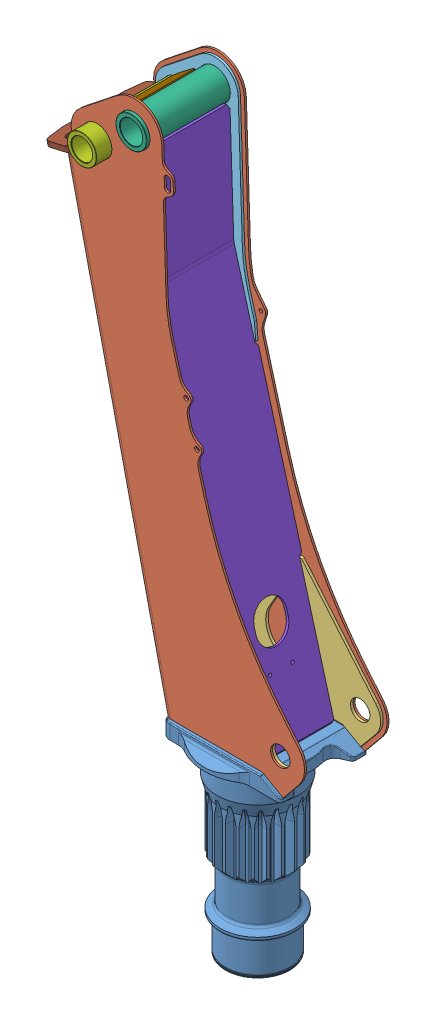
SolidWorks assembly 6344051, configuration Default. Lengths in mm.
Overall size (806.83 2259.1 354).
15 component instances, 12 part files, 31 mates.
Components (placement in the parent):
- 6344052-1: 6344052 [Default] at origin size (370 610 330)
- 6344053-1: 6344053 [Default] at (-268.9944 20.2009 -130.1889) x (0.974956 0.222399 0) z (0 0 1) size (566.48 1735.19 260.58)
  - 6344054-1: 6344054 [Default] at origin size (438.19 1703.77 260.58)
  - 6344055-2: 6344055 [6344055] at (480 -4.567 246.3777) x (0.974956 -0.222399 0) z (0 0 1) size (406.29 417 8)
  - 6344055-1: 6344055 [6344056] at (480 -4.567 6) x (0.974956 -0.222399 0) z (0 0 1) size (406.29 417 8)
  - 6344057-1: 6344057 [Default med affasning + nedslibning af spids] at (122.8111 3 130.1889) x (0 -1 0) z (1 0 0) size (320 185 10)
  - 6344058-1: 6344058 [Default] at (362.8595 1505.2986 6) x (0.974956 -0.222399 0) z (0 0 1) size (310 700 7)
  - 6344058-2: 6344058 [Default] at (362.8595 1505.2986 247.3777) x (0.974956 -0.222399 0) z (0 0 1) size (310 700 7)
- 6344059-1: 6344059 [boret] at (-250 1568.5 0) x (0 0 1) z (0.5 -0.866025 0) size (280 95 95)
- 6344061-1: 6344061 [boret] at (-365 1483.5 0) x (0 0 1) z (0.5 -0.866025 0) size (354 90 90)
- 6344062-1: 6344062 [Default] at (121.7385 48.8771 0) x (0 0 1) z (-0.964109 -0.265508 0) size (248 1528.91 93.1)
- 6344063-1: 6344063 [Default] at (-371.2649 1535.397 0) x (0 0 -1) z (0.608359 -0.793662 0) size (231 90 8)
- 6344065-1: 6344065 [Default] at (-401.9244 1447.417 0) x (0 0 -1) z (0.974956 0.222399 0) size (231 125 8)
- 6344066-1: 6344066 [Default] at (-469.5822 1424.7701 0) x (0 0 1) z (-0.222399 0.974956 0) size (318 109.52 26)
- 6344064-1: 6344064 [Default] at (125.6828 157.1547 138.1889) x (-0.906308 0.422618 0) z (0 0 -1) size (50.57 60 8)
Mates (geometry in assembly coordinates):
- Distance3: distance = 250 mm: line of 6344053-1/6344054-1 through (-250 1568.5 -124.1889) axis (0 0 -1); plane of assembly through (0 0 0) normal (1 0 0)
- Concentric1: concentric anti-aligned: cylinder of 6344053-1/6344054-1 through (-250 1568.5 124.1889) axis (0 0 1) radius 48.5; cylinder of 6344059-1 through (-250 1568.5 -140) axis (0 0 -1) radius 47.5
- Coincident5: coincident aligned: plane of 6344059-1 through (-250 1568.5 0) normal (0 0 1); plane of assembly through (0 0 0) normal (0 0 1)
- Angle1: planar angle = 2.617994 rad aligned: plane of 6344059-1 through (-250 1568.5 0) normal (-0.866025 -0.5 0); plane of assembly through (0 0 0) normal (1 0 0)
- Concentric2: concentric anti-aligned: cylinder of 6344053-1/6344054-1 through (-365 1483.5 124.1889) axis (0 0 1) radius 46; cylinder of 6344061-1 through (-365 1483.5 -177) axis (0 0 -1) radius 45
- Coincident7: coincident aligned: plane of 6344061-1 through (-365 1483.5 0) normal (0 0 1); plane of assembly through (0 0 0) normal (0 0 1)
- Angle2: planar angle = 2.617994 rad aligned: plane of 6344061-1 through (-365 1483.5 0) normal (-0.866025 -0.5 0); plane of assembly through (0 0 0) normal (1 0 0)
- Distance5: distance = 65 mm anti-aligned: plane of 6344053-1/6344054-1 through (-469.07 1449.5035 -136.8356) normal (0.974956 0.222399 0); plane of 6344065-1 through (-375.2365 1330.4224 0) normal (-0.974956 -0.222399 0)
- Coincident9: coincident: cylinder of 6344061-1 through (-365 1483.5 -177) axis (0 0 -1) radius 45; line of 6344065-1 through (-394.1248 1449.1962 -103.8944) axis (0 0 1)
- Coincident10: coincident anti-aligned: plane of 6344065-1 through (-401.9244 1447.417 0) normal (0 0 -1); plane of assembly through (0 0 0) normal (0 0 1)
- Coincident11: coincident aligned: plane of 6344066-1 through (-469.5822 1424.7701 0) normal (0 0 1); plane of assembly through (0 0 0) normal (0 0 1)
- Coincident12: coincident anti-aligned: plane of 6344053-1/6344054-1 through (-474.9198 1448.1691 -136.8356) normal (-0.974956 -0.222399 0); plane of 6344066-1 through (-472.9182 1439.3945 -114) normal (0.974956 0.222399 0)
- Distance6: distance = 6 mm aligned: plane of 6344053-1/6344054-1 through (-465.7341 1434.8791 -136.8356) normal (-0.222399 0.974956 0); plane of 6344066-1 through (-404.6713 1454.9624 156) normal (-0.222399 0.974956 0)
- Coincident14: coincident aligned: plane of 6344062-1 through (121.7385 48.8771 0) normal (0 0 1); plane of assembly through (0 0 0) normal (0 0 1)
- Coincident15: coincident: cylinder of 6344059-1 through (-250 1568.5 -140) axis (0 0 -1) radius 47.5; line of 6344062-1 through (-209.6483 1543.4403 104.3944) axis (0 0 -1)
- Parallel1: parallel aligned: plane of 6344053-1/6344054-1 through (-165.0443 1571.2441 -124.1889) normal (0.999479 0.032283 0); plane of 6344062-1 through (-150.8366 9.5465 -108.6459) normal (0.999452 0.033105 0)
- Tangent1: tangent aligned: cylinder of 6344059-1 through (-250 1568.5 -140) axis (0 0 -1) radius 47.5; plane of 6344062-1 through (-150.8366 9.5465 -108.6459) normal (0.999452 0.033105 0)
- Coincident17: coincident anti-aligned: plane of 6344053-1/6344054-1 through (-722.2141 1391.7582 130.1889) normal (0 0 1); plane of 6344064-1 through (125.6828 157.1547 130.1889) normal (0 0 -1)
- Coincident18: coincident: line of 6344053-1/6344054-1 through (200 122.5 124.1889) axis (0 0 1); plane of 6344064-1 through (125.6828 157.1547 138.1889) normal (0.422618 0.906308 0)
- Distance7: distance = 82 mm: line of 6344053-1/6344054-1 through (200 122.5 124.1889) axis (0 0 1); plane of 6344064-1 through (125.6828 157.1547 138.1889) normal (-0.906308 0.422618 0)
- Angle3: planar angle = 3.577925 rad anti-aligned: plane of 6344064-1 through (125.6828 157.1547 138.1889) normal (0.422618 0.906308 0); plane of assembly through (0 0 0) normal (0 1 0)
- Coincident19: coincident anti-aligned: plane of 6344059-1 through (-250 1568.5 0) normal (0 0 1); plane of 6344063-1 through (-371.2649 1535.397 0) normal (0 0 -1)
- Coincident21: coincident: cylinder of 6344059-1 through (-250 1568.5 -140) axis (0 0 -1) radius 47.5; line of 6344063-1 through (-294.9684 1583.8 -103.8944) axis (0 0 1)
- Tangent3: tangent aligned: cylinder of 6344059-1 through (-250 1568.5 -140) axis (0 0 -1) radius 47.5; plane of 6344063-1 through (-368.8839 1537.2221 -103.8944) normal (-0.608359 0.793662 0)
- Tangent4: tangent aligned: cylinder of 6344061-1 through (-365 1483.5 -177) axis (0 0 -1) radius 45; plane of 6344063-1 through (-368.8839 1537.2221 -103.8944) normal (-0.608359 0.793662 0)
- Distance8: distance = 95 mm: line of 6344053-1/6344055-1 through (200 122.5 -116.1889) axis (0 0 -1); plane of 6344062-1 through (120.942 51.7694 -108.6459) normal (0.964109 0.265508 0)
- Coincident22: coincident aligned: plane of 6344052-1 through (0 0 0) normal (1 0 0); plane of assembly through (0 0 0) normal (1 0 0)
- Coincident23: coincident aligned: plane of 6344052-1 through (0 0 0) normal (0 0 1); plane of assembly through (0 0 0) normal (0 0 1)
- Coincident24: coincident aligned: plane of 6344052-1 through (0 0 0) normal (0 1 0); plane of assembly through (0 0 0) normal (0 1 0)
- Distance9: distance = 2 mm anti-aligned: plane of 6344052-1 through (188.4846 45 -49.9855) normal (0 1 0); plane of 6344053-1/6344054-1 through (-150.3861 47 124.1889) normal (0 -1 0)
- Coincident26: coincident aligned: plane of 6344053-1/6344054-1 through (-268.9944 20.2009 0) normal (0 0 1); plane of assembly through (0 0 0) normal (0 0 1)
